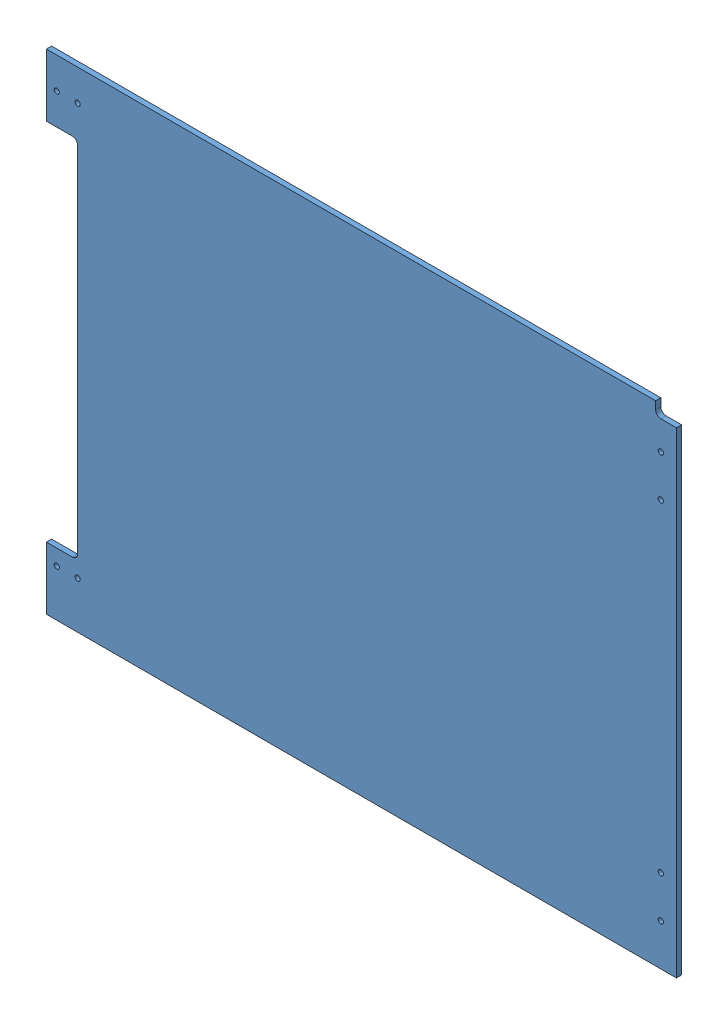
SolidWorks assembly GE-19079-Left-Blue, configuration Default. Lengths in mm.
Overall size (768.35 596.9 44.58).
2 component instances, 2 part files, 3 mates.
Components (placement in the parent):
- GE-19079-1: GE-19079 [GE-19079] at origin size (768.35 596.9 6.35)
- GE-19079-Left-Blue-Vinyl-1: GE-19079-Left-Blue-Vinyl [Notched] at (0 0 -0.127) size (768.35 596.9 0.13)
Mates (geometry in assembly coordinates):
- Coincident1: coincident: plane of assembly; plane of assembly; plane of GE-19079-1 through (0 0 0) normal (0 0 -1); plane of GE-19079-Left-Blue-Vinyl-1 through (0 0 0) normal (0 0 1)
- Coincident2: coincident: plane of assembly; plane of assembly; plane of GE-19079-1 through (-368.3 298.45 6.35) normal (0 1 0); plane of GE-19079-Left-Blue-Vinyl-1 through (-368.3 298.45 0) normal (0 1 0)
- Coincident3: coincident: plane of assembly; plane of assembly; plane of GE-19079-1 through (368.3 -298.45 6.35) normal (1 0 0); plane of GE-19079-Left-Blue-Vinyl-1 through (368.3 -298.45 0) normal (1 0 0)
